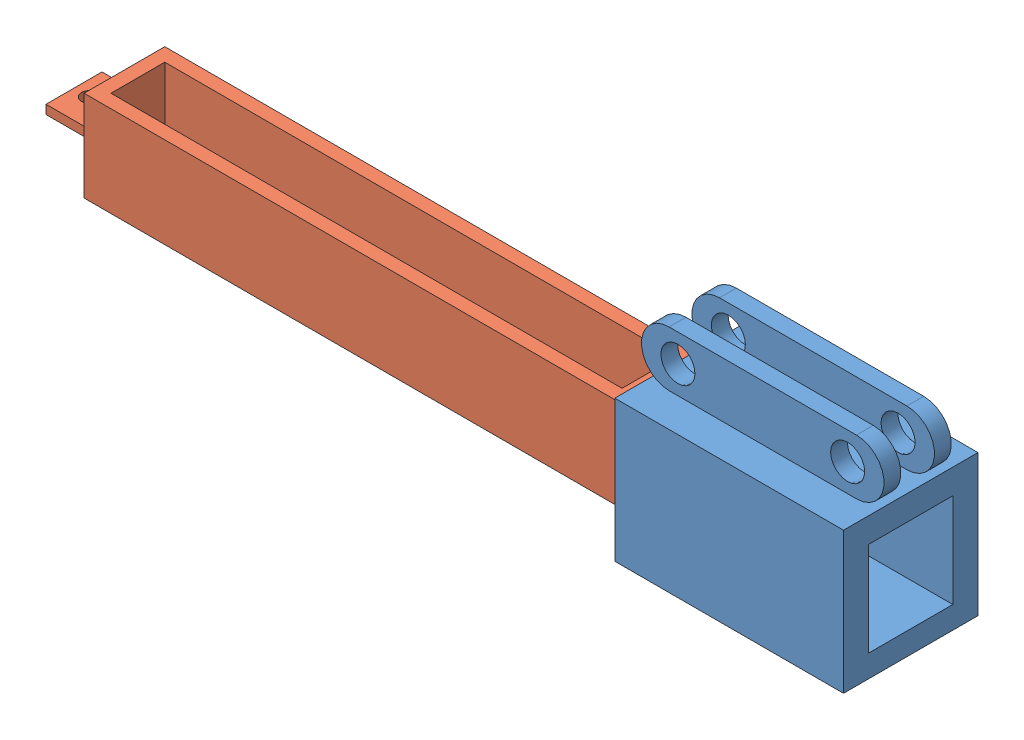
SolidWorks assembly Lower_Assembly, configuration Default. Lengths in mm.
Overall size (250.93 58.45 40).
2 component instances, 2 part files, 2 mates.
Components (placement in the parent):
- Lower_Base-1: Lower_Base [Default] at (-14.973 51.8913 -6.8208) size (72.14 58.45 40)
- cartridge-1: cartridge [Default] at (-214.833 8.2927 5.1792) x (0 0 -1) z (1 0 0) size (24 27 175)
Mates (geometry in assembly coordinates):
- Width1: width anti-aligned: plane of Lower_Base-1 through (-51.0442 36.2927 -19.3208) normal (0 0 1); plane of cartridge-1 through (-51.0442 36.2927 5.6792) normal (0 0 -1); plane of Lower_Base-1 through (-54.833 8.2927 -18.8208) normal (0 0 -1); plane of cartridge-1 through (-54.833 8.2927 5.1792) normal (0 0 1)
- Coincident1: coincident anti-aligned: plane of Lower_Base-1 through (-51.0442 8.2927 -19.3208) normal (0 1 0); plane of cartridge-1 through (-54.833 8.2927 5.1792) normal (0 -1 0)
